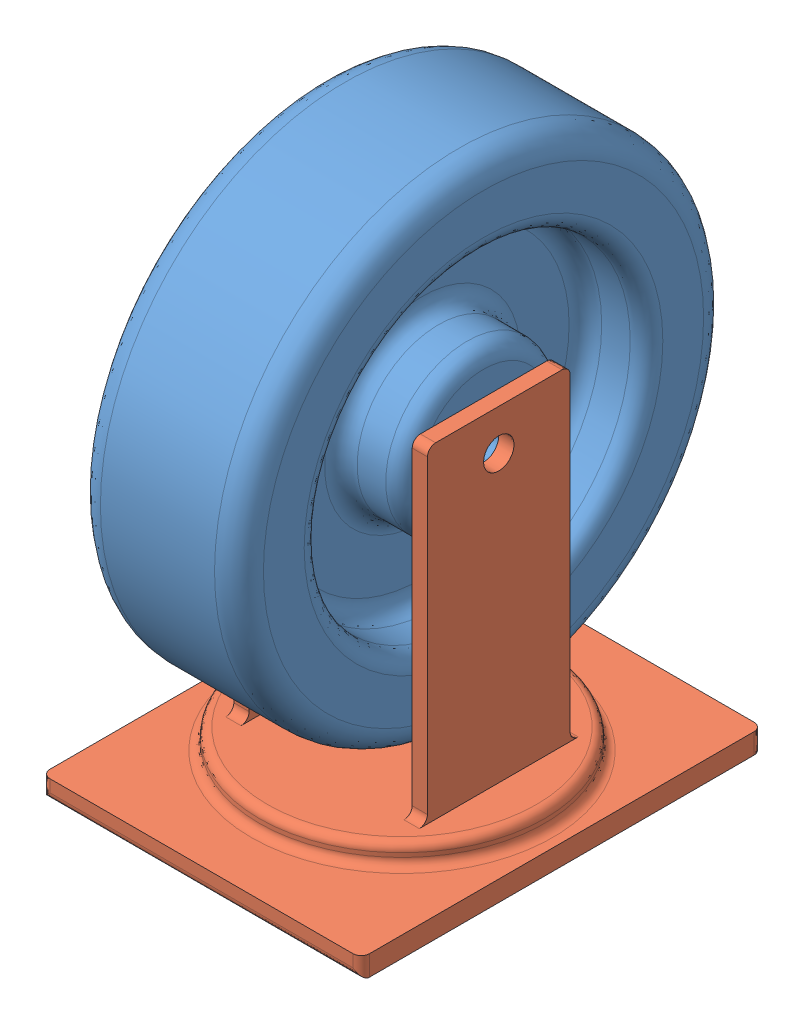
SolidWorks assembly wheel_assembly, configuration Default. Lengths in mm.
Overall size (99.57 177.8 152.4).
2 component instances, 2 part files, 2 mates.
Components (placement in the parent):
- wheel-1: wheel [Default] at (-26.5523 104.0356 130.9582) size (50.8 152.4 152.4)
- wheel_housing-1: wheel_housing [Default] at (48.6317 2.4356 193.4422) x (0 1 0) z (0 0 1) size (114.3 99.57 124.97)
Mates (geometry in assembly coordinates):
- Concentric1: concentric anti-aligned: circle of wheel-1; circle of wheel_housing-1
- Coincident2: coincident anti-aligned: plane of wheel-1 through (24.2477 104.0356 130.9582) normal (1 0 0); plane of wheel_housing-1 through (24.2477 116.7356 153.1832) normal (-1 0 0)
